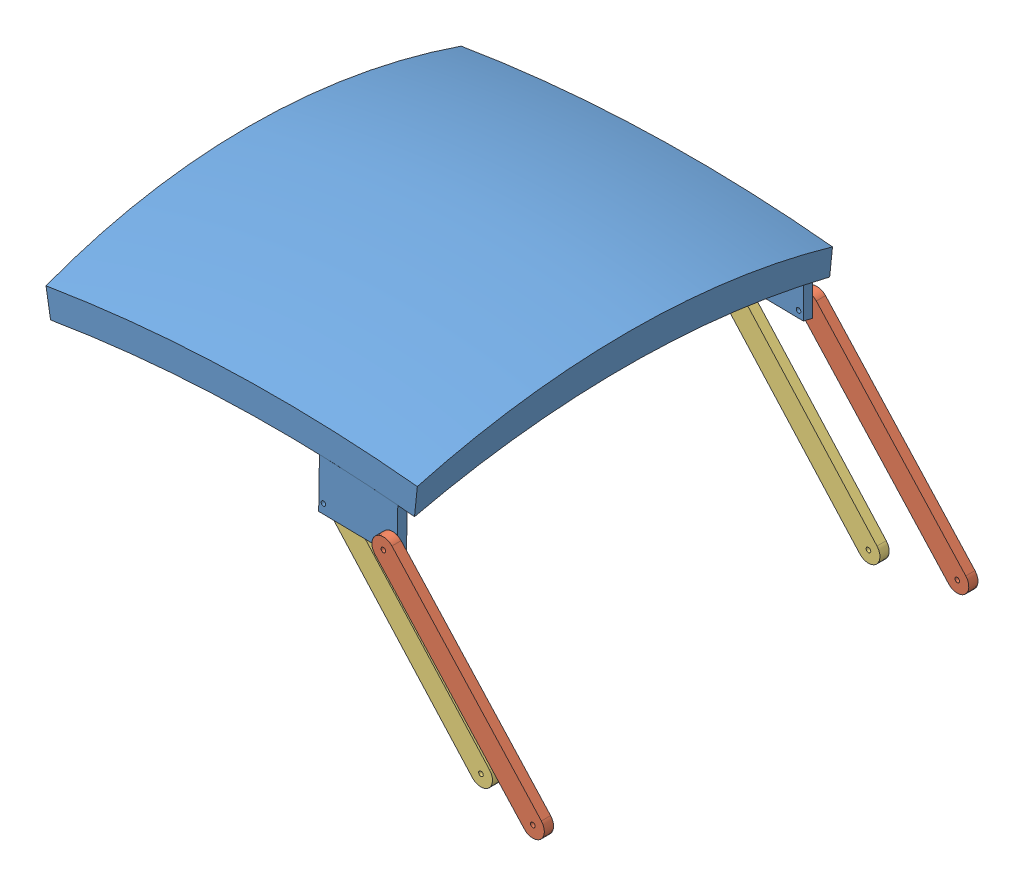
SolidWorks assembly Roof Assembly, configuration Default. Lengths in mm.
Overall size (1124.96 1284.64 940).
5 component instances, 3 part files, 11 mates.
Components (placement in the parent):
- Roof  2021-1: Roof  2021 [Default] at (594.3152 459.0763 929.0689) x (0.999884 -0.015247 0) z (0 0 1) size (156.15 809.39 880)
- Rear Rocker-1: Rear Rocker [Default] at (712.7372 113.3021 963.8006) x (0.737782 0.675039 0) z (0 0 1) size (6.25 66.25 2.5)
- Front Rocker-1: Front Rocker [Default] at (685.2384 -97.3864 923.8006) x (0.742546 0.669795 0) z (0 0 1) size (6.25 66.25 2.5)
- Rear Rocker-2: Rear Rocker [Default] at (712.7372 113.3021 43.8006) x (0.737782 0.675039 0) z (0 0 1) size (6.25 66.25 2.5)
- Front Rocker-2: Front Rocker [Default] at (685.2384 -97.3864 83.8006) x (0.742546 0.669795 0) z (0 0 1) size (6.25 66.25 2.5)
Mates (geometry in assembly coordinates):
- Concentric2: concentric aligned: cylinder of Roof  2021-1 through (532.2832 273.4938 963.8006) axis (0 0 1) radius 5; cylinder of Rear Rocker-1 through (532.2832 273.4938 983.8006) axis (0 0 1) radius 5
- Coincident2: coincident anti-aligned: plane of Rear Rocker-1 through (856.3021 -80.6415 963.8006) normal (0 0 -1); plane of Roof  2021-1 through (278.525 -2592.3859 963.8006) normal (0 0 1)
- Concentric4: concentric aligned: cylinder of Roof  2021-1 through (382.3006 275.7808 963.8006) axis (0 0 1) radius 5; cylinder of Front Rocker-1 through (382.3006 275.7808 943.8006) axis (0 0 1) radius 5
- Concentric6: concentric aligned: cylinder of Roof  2021-1 through (532.2832 273.4938 963.8006) axis (0 0 1) radius 5; cylinder of Rear Rocker-2 through (532.2832 273.4938 63.8006) axis (0 0 1) radius 5
- Concentric8: concentric aligned: cylinder of Roof  2021-1 through (382.3006 275.7808 963.8006) axis (0 0 1) radius 5; cylinder of Front Rocker-2 through (382.3006 275.7808 103.8006) axis (0 0 1) radius 5
- Coincident3: coincident anti-aligned: plane of Roof  2021-1 through (1439.2495 -2244.3652 891.6032) normal (0 0 1); plane of Front Rocker-1 through (721.5992 363.7757 891.6032) normal (0 0 -1)
- Coincident4: coincident anti-aligned: plane of Roof  2021-1 through (1439.2495 -2244.3652 -8.3968) normal (0 0 -1); plane of Rear Rocker-2 through (870.382 382.8459 -8.3968) normal (0 0 1)
- Coincident5: coincident anti-aligned: plane of Roof  2021-1 through (1439.2495 -2244.3652 -8.3968) normal (0 0 -1); plane of Front Rocker-2 through (721.5992 363.7757 -8.3968) normal (0 0 1)
- Coincident6: coincident anti-aligned: plane of Roof  2021-1 through (235.7609 -3084.3476 943.8006) normal (0 0 -1); plane of Front Rocker-1 through (703.8021 -80.6415 943.8006) normal (0 0 1)
- Coincident7: coincident anti-aligned: plane of Roof  2021-1 through (235.7609 -3084.3476 83.8006) normal (0 0 1); plane of Front Rocker-2 through (703.8021 -80.6415 83.8006) normal (0 0 -1)
- Coincident8: coincident anti-aligned: plane of Roof  2021-1 through (278.525 -2592.3859 63.8006) normal (0 0 -1); plane of Rear Rocker-2 through (856.3021 -80.6415 63.8006) normal (0 0 1)
